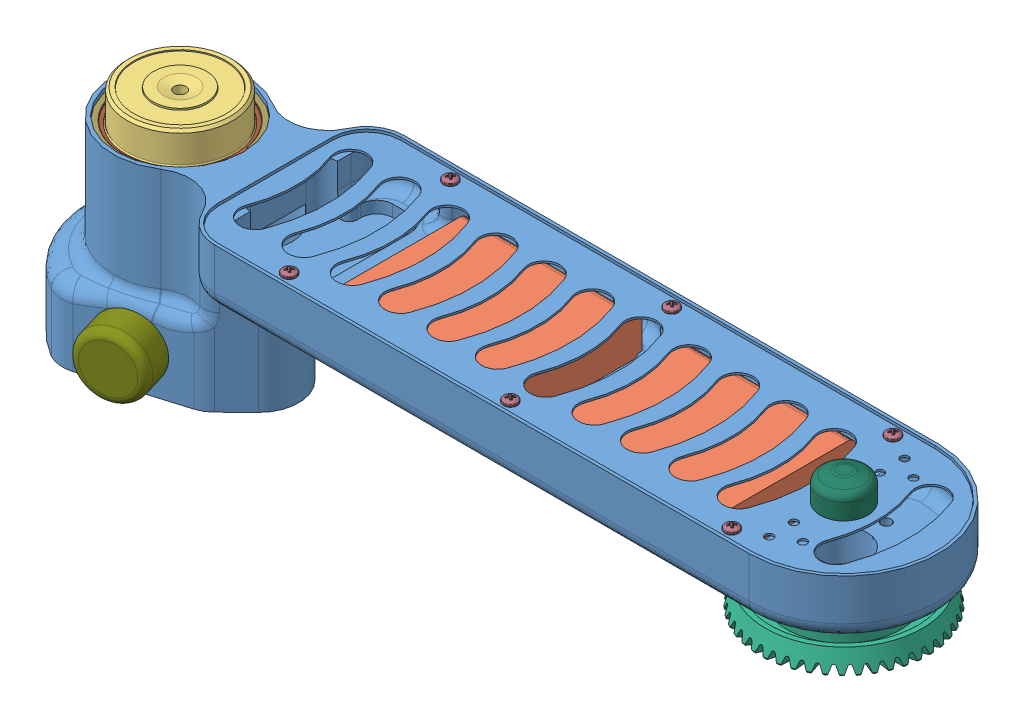
SolidWorks assembly 1001-2003 BATTERY LINK ASSY, configuration replacement encoder. Lengths in mm.
Overall size (351.62 112.52 93.62).
54 component instances, 21 part files, 75 mates.
Components (placement in the parent):
- 1001-3013,3014,3015 BATTERY LINK HOUSING & COVERS-1: 1001-3013,3014,3015 BATTERY LINK HOUSING & COVERS [Default] at origin size (342.9 76.2 76.2)
- 1001-3013,3014,3015 BATTERY LINK HOUSING & COVERS-3: 1001-3013,3014,3015 BATTERY LINK HOUSING & COVERS [palmar cover] at origin size (265.18 0.79 73.41)
- 1001-3013,3014,3015 BATTERY LINK HOUSING & COVERS-4: 1001-3013,3014,3015 BATTERY LINK HOUSING & COVERS [dorsal cover] at origin size (82.93 0.79 67.11)
- Battery 18650-1: Battery 18650 [Default] at (-92.71 10.3683 0) x (0 0 -1) z (1 0 0) size (55 18 70)
- Battery 18650-2: Battery 18650 [Default] at (-108.585 10.3683 0) x (0 0 1) z (-1 0 0) size (55 18 70)
- 1001-2001 ELECTROMAGNET ASSY-1: 1001-2001 ELECTROMAGNET ASSY [rev 03] at (-266.7 9.4082 0) x (-1 0 0) z (0 0 -1) size (50.7 33.97 50.7)
  - 1001-3001,3002,3003,3004,0002 ELECTROMAGNET PARENT-5: 1001-3001,3002,3003,3004,0002 ELECTROMAGNET PARENT [rev 03 core] at origin size (21.31 33.97 21.31)
  - 1001-3001,3002,3003,3004,0002 ELECTROMAGNET PARENT-7: 1001-3001,3002,3003,3004,0002 ELECTROMAGNET PARENT [rev 03] at origin size (50.7 33.01 50.7)
  - 1001-3001,3002,3003,3004,0002 ELECTROMAGNET PARENT-8: 1001-3001,3002,3003,3004,0002 ELECTROMAGNET PARENT [rev 03 spool] at origin size (36.73 28.47 36.73)
  - 1001-3001,3002,3003,3004,0002 ELECTROMAGNET PARENT-9: 1001-3001,3002,3003,3004,0002 ELECTROMAGNET PARENT [rev 02 coils] at origin size (36.73 26.95 36.73)
- Bearing - Delrin 6455K640-3: Bearing - Delrin 6455K640 [6455K64] at (-266.7 4.5974 0) x (0.689582 0 -0.724208) z (0 -1 0) size (28.57 28.57 6.35)
- Bearing - Delrin 6455K640-2: Bearing - Delrin 6455K640 [6455K64] at (-266.7 -12.8524 0) x (0.125826 0 -0.992052) z (0 -1 0) size (28.57 28.57 6.35)
- 1001-3001,3002,3003,3004,0002 ELECTROMAGNET PARENT-2: 1001-3001,3002,3003,3004,0002 ELECTROMAGNET PARENT [shaft] at (-266.7 9.4082 0) x (-0.98953 0 0.144326) z (-0.144326 0 -0.98953) size (12.78 36.2 12.78)
- Retaining Ring 99142A480-3: Retaining Ring 99142A480 [99142A480] at (-266.7 -8.4074 0) x (0.903607 0 0.428363) z (-0.428363 0 0.903607) size (31.72 1.27 34.32)
- Retaining Ring 99142A480-2: Retaining Ring 99142A480 [99142A480] at (-266.7 0.1524 0) x (0.943591 0 -0.331114) z (-0.331114 0 -0.943591) size (31.72 1.27 34.32)
- 1001-3011 MODIFIED DRIVEN GEAR-1: 1001-3011 MODIFIED DRIVEN GEAR [modified] at (0 -4.3198 0) x (-0.866025 0 -0.5) z (-0.5 0 0.866025) size (68.51 10.99 68.55)
- Canon TR-36-1: Canon TR-36 [Default] at (-239.7 -34.78 0) x (0 0 -1) z (0 1 0) size (40 47 17) (suppressed, hidden)
- 98381A438 (1)-1: 98381A438 (1) [98381A438] at (-283.21 4.0132 0) x (0 1 0) z (-0.942328 0 0.334692) size (12.7 2.38 2.38)
- User Library-5mm led w_bushing-1: User Library-5mm led w_bushing [Default] at (-266.7 -38.8049 0) x (1 0 0) z (0 -1 0) size (7.72 8.43 36.02)
- 98511A521-7: 98511A521 [98511A521] at (0 11.9568 17) x (0.27318 0 -0.961963) z (0 1 0) size (7.92 7.92 18.45)
- Oring -133 McMaster 5577K133-1: Oring -133 McMaster 5577K133 [Default] at (-266.7 26.67 0) x (0.946468 0 0.322797) z (0 1 0) size (50.93 50.93 2.62)
- 1001-3005 ELECTROMAGNET STATOR SHIM-1: 1001-3005 ELECTROMAGNET STATOR SHIM [Default] at (-266.7 28.8138 0) size (50.42 0.1 50.42)
- 1001-3005 ELECTROMAGNET STATOR SHIM-2: 1001-3005 ELECTROMAGNET STATOR SHIM [Default] at (-266.7 28.9154 0) size (50.42 0.1 50.42)
- 1001-3005 ELECTROMAGNET STATOR SHIM-3: 1001-3005 ELECTROMAGNET STATOR SHIM [Default] at (-266.7 29.017 0) size (50.42 0.1 50.42)
- 1001-3005 ELECTROMAGNET STATOR SHIM-4: 1001-3005 ELECTROMAGNET STATOR SHIM [Default] at (-266.7 29.1186 0) size (50.42 0.1 50.42)
- VH_200-1: VH_200 [Default] at (-266.7 29.7301 0) size (51.85 0.82 52.25)
- 98511A521-9: 98511A521 [98511A521] at (-14.7224 11.9568 8.5) x (0.969674 0 -0.244401) z (0 1 0) size (7.92 7.92 18.45)
- 98511A521-10: 98511A521 [98511A521] at (-14.7224 11.9568 -8.5) x (0.696494 0 0.717562) z (0 1 0) size (7.92 7.92 18.45)
- 98511A521-11: 98511A521 [98511A521] at (0 11.9568 -17) x (-0.27318 0 0.961963) z (0 1 0) size (7.92 7.92 18.45)
- 98511A521-12: 98511A521 [98511A521] at (14.7224 11.9568 -8.5) x (-0.969674 0 0.244401) z (0 1 0) size (7.92 7.92 18.45)
- 98511A521-13: 98511A521 [98511A521] at (14.7224 11.9568 8.5) x (-0.696494 0 -0.717562) z (0 1 0) size (7.92 7.92 18.45)
- 96562A106-1: 96562A106 [96562A106] at (-279.4 -37.3062 29.845) x (0.996675 0 -0.081481) z (0 -1 0) size (5.56 5.56 27.75)
- 96562A106-2: 96562A106 [96562A106] at (-279.4 -37.3062 -29.845) x (0.996675 0 -0.081481) z (0 -1 0) size (5.56 5.56 27.75)
- 96562A106-3: 96562A106 [96562A106] at (-190.5 24.4157 -32.385) x (-0.78982 0 -0.613339) z (0 1 0) size (5.56 5.56 27.75)
- 96562A106-4: 96562A106 [96562A106] at (-190.5 24.4157 32.385) x (-0.78982 0 -0.613339) z (0 1 0) size (5.56 5.56 27.75)
- 96562A106-5: 96562A106 [96562A106] at (-101.6 24.4157 32.385) x (-0.78982 0 -0.613339) z (0 1 0) size (5.56 5.56 27.75)
- 96562A106-6: 96562A106 [96562A106] at (-12.7 24.4157 32.385) x (-0.78982 0 -0.613339) z (0 1 0) size (5.56 5.56 27.75)
- 96562A106-7: 96562A106 [96562A106] at (-101.6 24.4157 -32.385) x (-0.78982 0 -0.613339) z (0 1 0) size (5.56 5.56 27.75)
- 96562A106-8: 96562A106 [96562A106] at (-12.7 24.4157 -32.385) x (-0.78982 0 -0.613339) z (0 1 0) size (5.56 5.56 27.75)
- 90272A091-1: 90272A091 [90272A091] at (-284.7 -14.0175 0) x (1 0 0) z (0 -1 0) size (4.9 4.9 6.71) (suppressed, hidden)
- 90272A091-2: 90272A091 [90272A091] at (-257.7 -14.0175 15.5885) x (-0.5 0 -0.866025) z (0 -1 0) size (4.9 4.9 6.71)
- 90272A091-3: 90272A091 [90272A091] at (-257.7 -14.0175 -15.5885) x (-0.5 0 0.866025) z (0 -1 0) size (4.9 4.9 6.71)
- 98381A438 (1)-3: 98381A438 (1) [98381A438] at (-270.5958 8.1382 0.5682) x (0 -1 0) z (-0.60583 0 -0.795594) size (12.7 2.38 2.38)
- 1001-3012 BALL GLIDER-1: 1001-3012 BALL GLIDER [Default] at (0 30.7658 0) x (0.866025 0 0.5) z (-0.5 0 0.866025) size (19.05 11.03 19.05)
- 96562A106-9: 96562A106 [96562A106] at (5.715 36.322 0) x (0.996675 0 -0.081481) z (0 -1 0) size (5.56 5.56 27.75)
- 96562A106-10: 96562A106 [96562A106] at (-2.8575 36.322 4.9493) x (-0.427773 0 0.903886) z (0 -1 0) size (5.56 5.56 27.75)
- 96562A106-11: 96562A106 [96562A106] at (-2.8575 36.322 -4.9493) x (-0.568902 0 -0.822405) z (0 -1 0) size (5.56 5.56 27.75)
- Bumper 9541K3-1: Bumper 9541K3 [Default] at (-257.9158 -29.5275 29.1868) x (0.916943 -0.288196 -0.275968) z (-0.275968 -0.957571 0.083057) size (25.4 22.23 25.4)
- Bumper 9541K3-2: Bumper 9541K3 [Default] at (-257.9158 -29.5275 -29.1868) x (-0.916943 -0.288196 -0.275968) z (0.275968 -0.957571 0.083057) size (25.4 22.23 25.4)
- Locknut 94820A225-1: Locknut 94820A225 [94820A225] at (-258.6478 -29.5275 26.7545) x (0.957571 0 -0.288196) z (0.288196 0 0.957571) size (9.53 11 6.84)
- Locknut 94820A225-2: Locknut 94820A225 [94820A225] at (-258.6478 -29.5275 -26.7545) x (-0.957571 0 -0.288196) z (0.288196 0 -0.957571) size (9.53 11 6.84)
- E7P-X-197-S-C-T-X-1: E7P-X-197-S-C-T-X [Default] at (-266.7 -17.907 0) x (-0.056079 0 0.998426) z (0.998426 0 0.056079)
- Retaining Ring 97633A200-1: Retaining Ring 97633A200 [97633A200] at (-266.7 -16.4719 0) x (0 1 0) z (0 0 1) size (0.89 19.18 19.18)
- 91251A113-1: 91251A113 [91251A113] at (-266.7 3.6932 0) x (0.186333 0 -0.982487) z (0 -1 0) size (4.65 4.65 22.59)
Mates (geometry in assembly coordinates):
- Coincident38: coincident anti-aligned: plane of 1001-3013,3014,3015 BATTERY LINK HOUSING & COVERS-1 through (0 0 0) normal (0 0 1); plane of Battery 18650-1 through (-92.71 10.3683 0) normal (0 0 -1)
- Coincident41: coincident aligned: plane of Battery 18650-1; plane of Battery 18650-2
- Coincident42: coincident anti-aligned: plane of Battery 18650-1 through (-92.71 10.3683 0) normal (0 0 -1); plane of Battery 18650-2 through (-108.585 10.3683 0) normal (0 0 1)
- Coincident43: coincident anti-aligned: line of 1001-3013,3014,3015 BATTERY LINK HOUSING & COVERS-1 through (-266.7 -48.26 0) axis (0 1 0); line of ? through (-266.7 43.4918 0) axis (0 -1 0)
- Coincident482: coincident anti-aligned: line of 1001-3013,3014,3015 BATTERY LINK HOUSING & COVERS-1 through (0 35.56 0) axis (0 -1 0); line of 1001-3011 MODIFIED DRIVEN GEAR-1 through (0 -9.7067 0) axis (0 1 0)
- Angle1: planar angle = 0.523599 rad aligned: plane of 1001-3011 MODIFIED DRIVEN GEAR-1 through (0 -4.3198 0) normal (-0.5 0 0.866025); plane of assembly through (0 0 0) normal (0 0 1)
- Coincident484: coincident anti-aligned: line of 1001-3013,3014,3015 BATTERY LINK HOUSING & COVERS-1 through (-266.7 -48.26 0) axis (0 1 0); line of 1001-3001,3002,3003,3004,0002 ELECTROMAGNET PARENT-2 through (-266.7 42.9768 0) axis (0 -1 0)
- Coincident485: coincident aligned: line of 1001-3013,3014,3015 BATTERY LINK HOUSING & COVERS-1 through (-266.7 -48.26 0) axis (0 1 0); line of Retaining Ring 99142A480-2 through (-266.7 0.0889 0) axis (0 1 0)
- Coincident486: coincident anti-aligned: line of 1001-3013,3014,3015 BATTERY LINK HOUSING & COVERS-1 through (-266.7 -48.26 0) axis (0 1 0); line of Retaining Ring 99142A480-3 through (-266.7 -8.3439 0) axis (0 -1 0)
- Coincident487: coincident aligned: line of 1001-3013,3014,3015 BATTERY LINK HOUSING & COVERS-1 through (-266.7 -48.26 0) axis (0 1 0); line of Bearing - Delrin 6455K640-2 through (-266.7 -9.6774 0) axis (0 1 0)
- Coincident488: coincident aligned: line of 1001-3013,3014,3015 BATTERY LINK HOUSING & COVERS-1 through (-266.7 -48.26 0) axis (0 1 0); line of Bearing - Delrin 6455K640-3 through (-266.7 7.7724 0) axis (0 1 0)
- Coincident489: coincident anti-aligned: plane of 1001-3013,3014,3015 BATTERY LINK HOUSING & COVERS-1 through (-280.8986 0.1524 0) normal (0 1 0); plane of Retaining Ring 99142A480-2 through (-263.1045 0.1524 -13.0915) normal (0 -1 0)
- Coincident490: coincident anti-aligned: plane of 1001-3013,3014,3015 BATTERY LINK HOUSING & COVERS-1 through (-281.9146 -8.4074 0) normal (0 -1 0); plane of Retaining Ring 99142A480-3 through (-264.499 -8.4074 13.3967) normal (0 1 0)
- Coincident491: coincident anti-aligned: plane of Bearing - Delrin 6455K640-2 through (-252.841 -9.6774 1.7578) normal (0 1 0); plane of Retaining Ring 99142A480-3 through (-264.499 -9.6774 13.3967) normal (0 -1 0)
- Coincident492: coincident anti-aligned: plane of Bearing - Delrin 6455K640-3 through (-256.5828 1.4224 9.6335) normal (0 -1 0); plane of Retaining Ring 99142A480-2 through (-263.1045 1.4224 -13.0915) normal (0 1 0)
- Distance13: distance = 0.7595 mm anti-aligned: plane of 1001-3013,3014,3015 BATTERY LINK HOUSING & COVERS-1 through (-280.8986 7.8232 0) normal (0 1 0); plane of 1001-2001 ELECTROMAGNET ASSY-1/1001-3001,3002,3003,3004,0002 ELECTROMAGNET PARENT-7 through (-248.412 8.5827 0) normal (0 -1 0)
- Coincident497: coincident anti-aligned: plane of ? through (-266.7 9.4082 0) normal (0 0 -1); plane of assembly through (0 0 0) normal (0 0 1)
- Concentric1: concentric aligned: cylinder of 1001-3013,3014,3015 BATTERY LINK HOUSING & COVERS-1 through (-283.21 7.8232 0) axis (0 1 0) radius 1.1906; cylinder of 98381A438 (1)-1 through (-283.21 -2.3368 0) axis (0 1 0) radius 1.1906
- Distance14: distance = 2.54 mm aligned: plane of 1001-3013,3014,3015 BATTERY LINK HOUSING & COVERS-1 through (-280.8986 7.8232 0) normal (0 1 0); plane of 98381A438 (1)-1 through (-283.21 10.3632 0) normal (0 1 0)
- Coincident5134: coincident anti-aligned: line of 1001-3013,3014,3015 BATTERY LINK HOUSING & COVERS-1 through (-266.7 -48.26 0) axis (0 1 0); line of Oring -133 McMaster 5577K133-1 through (-266.7 44.8023 0) axis (0 -1 0)
- Coincident5135: coincident anti-aligned: plane of 1001-2001 ELECTROMAGNET ASSY-1/1001-3001,3002,3003,3004,0002 ELECTROMAGNET PARENT-7 through (-244.6972 28.8138 0) normal (0 1 0); plane of 1001-3005 ELECTROMAGNET STATOR SHIM-1 through (-266.7 28.8138 0) normal (0 -1 0)
- Coincident5136: coincident aligned: line of 1001-3005 ELECTROMAGNET STATOR SHIM-1 through (-266.7 28.9204 0) axis (0 -1 0); line of ? through (-266.7 43.4918 0) axis (0 -1 0)
- Coincident5137: coincident anti-aligned: line of 1001-3005 ELECTROMAGNET STATOR SHIM-1 through (-266.7 28.9204 0) axis (0 -1 0); line of 1001-3013,3014,3015 BATTERY LINK HOUSING & COVERS-1 through (-266.7 -48.26 0) axis (0 1 0)
- Coincident5138: coincident anti-aligned: line of 1001-3013,3014,3015 BATTERY LINK HOUSING & COVERS-1 through (-266.7 -48.26 0) axis (0 1 0); line of VH_200-1 through (-266.7 30.1772 0) axis (0 -1 0)
- Coincident5139: coincident anti-aligned: plane of 1001-3013,3014,3015 BATTERY LINK HOUSING & COVERS-1 through (-292.825 30.1238 0) normal (0 -1 0); plane of VH_200-1 through (-240.773 30.1238 0) normal (0 1 0)
- Distance15: distance = 26.67 mm aligned: plane of Oring -133 McMaster 5577K133-1 through (-266.7 26.67 0) normal (0 1 0); plane of assembly through (0 0 0) normal (0 1 0)
- Concentric102: concentric anti-aligned: cylinder of 1001-3011 MODIFIED DRIVEN GEAR-1 through (0 -5.5692 17) axis (0 -1 0) radius 2.5527; cylinder of 98511A521-7 through (0 -5.5692 17) axis (0 1 0) radius 3.9624
- Coincident5140: coincident anti-aligned: plane of 1001-3011 MODIFIED DRIVEN GEAR-1 through (12.5117 -0.7432 7.2237) normal (0 -1 0); plane of 98511A521-7 through (0 -0.7432 17) normal (0 1 0)
- Coincident5141: coincident anti-aligned: plane of 1001-3013,3014,3015 BATTERY LINK HOUSING & COVERS-1 through (0 2.4308 0) normal (0 -1 0); plane of 1001-3011 MODIFIED DRIVEN GEAR-1 through (0 2.4308 0) normal (0 1 0)
- Coincident5142: coincident anti-aligned: plane of 1001-3013,3014,3015 BATTERY LINK HOUSING & COVERS-1 through (-234.95 10.3683 0) normal (0 1 0); plane of Battery 18650-1 through (-22.71 10.3683 24.325) normal (0 -1 0)
- Coincident5143: coincident anti-aligned: plane of 1001-3013,3014,3015 BATTERY LINK HOUSING & COVERS-1 through (-298.45 -17.78 0) normal (0 -1 0); plane of Canon TR-36-1 through (-266.7 -17.78 0) normal (0 1 0)
- Coincident5144: coincident anti-aligned: line of 1001-3013,3014,3015 BATTERY LINK HOUSING & COVERS-1 through (-266.7 -48.26 0) axis (0 1 0); line of Canon TR-36-1 through (-266.7 -18.78 0) axis (0 -1 0)
- Coincident5145: coincident anti-aligned: plane of Canon TR-36-1; plane of assembly through (0 0 0) normal (0 0 1)
- Coincident5146: coincident aligned: plane of 1001-3013,3014,3015 BATTERY LINK HOUSING & COVERS-3 through (0 0 0) normal (0 0 1); plane of assembly through (0 0 0) normal (0 0 1)
- Coincident5147: coincident aligned: plane of 1001-3013,3014,3015 BATTERY LINK HOUSING & COVERS-3 through (0 0 0) normal (0 1 0); plane of assembly through (0 0 0) normal (0 1 0)
- Coincident5148: coincident aligned: plane of 1001-3013,3014,3015 BATTERY LINK HOUSING & COVERS-3 through (0 0 0) normal (1 0 0); plane of assembly through (0 0 0) normal (1 0 0)
- Coincident5149: coincident aligned: plane of 1001-3013,3014,3015 BATTERY LINK HOUSING & COVERS-4 through (0 0 0) normal (0 0 1); plane of assembly through (0 0 0) normal (0 0 1)
- Coincident5150: coincident aligned: plane of 1001-3013,3014,3015 BATTERY LINK HOUSING & COVERS-4 through (0 0 0) normal (0 1 0); plane of assembly through (0 0 0) normal (0 1 0)
- Coincident5151: coincident aligned: plane of 1001-3013,3014,3015 BATTERY LINK HOUSING & COVERS-4 through (0 0 0) normal (1 0 0); plane of assembly through (0 0 0) normal (1 0 0)
- Concentric103: concentric aligned: cylinder of 1001-3013,3014,3015 BATTERY LINK HOUSING & COVERS-4 through (-266.7 -43.6562 0) axis (0 -1 0) radius 3.175; cylinder of User Library-5mm led w_bushing-1 through (-266.7 -49.028 0) axis (0 -1 0) radius 2.9972
- Coincident5152: coincident aligned: plane of 1001-3013,3014,3015 BATTERY LINK HOUSING & COVERS-4 through (-278.9455 -43.6562 -22.2533) normal (0 -1 0); circle of User Library-5mm led w_bushing-1
- Concentric104: concentric anti-aligned: cylinder of 1001-3013,3014,3015 BATTERY LINK HOUSING & COVERS-1 through (-279.4 -42.8625 29.845) axis (0 -1 0) radius 1.1303; cylinder of 96562A106-1 through (-279.4 -37.3062 29.845) axis (0 1 0) radius 2.7813
- Coincident5153: coincident anti-aligned: plane of 1001-3013,3014,3015 BATTERY LINK HOUSING & COVERS-4 through (-278.9455 -43.6562 -22.2533) normal (0 -1 0); plane of 96562A106-1 through (-279.4 -43.6562 29.845) normal (0 1 0)
- Coincident5154: coincident anti-aligned: plane of 1001-3013,3014,3015 BATTERY LINK HOUSING & COVERS-4 through (-278.9455 -43.6562 -22.2533) normal (0 -1 0); plane of 96562A106-2 through (-279.4 -43.6562 -29.845) normal (0 1 0)
- Concentric105: concentric anti-aligned: cylinder of 1001-3013,3014,3015 BATTERY LINK HOUSING & COVERS-4 through (-279.4 -43.6562 -29.845) axis (0 -1 0) radius 1.632; cylinder of 96562A106-2 through (-279.4 -37.3062 -29.845) axis (0 1 0) radius 2.7813
- Concentric106: concentric anti-aligned: cylinder of 96562A106-3 through (-190.5 24.4157 -32.385) axis (0 -1 0) radius 2.7813; cylinder of 1001-3013,3014,3015 BATTERY LINK HOUSING & COVERS-1 through (-190.5 29.972 -32.385) axis (0 1 0) radius 1.1303
- Coincident5155: coincident anti-aligned: plane of 1001-3013,3014,3015 BATTERY LINK HOUSING & COVERS-3 through (-214.757 30.7658 -22.987) normal (0 1 0); plane of 96562A106-3 through (-190.5 30.7658 -32.385) normal (0 -1 0)
- Coincident5156: coincident anti-aligned: plane of 1001-3013,3014,3015 BATTERY LINK HOUSING & COVERS-3 through (-214.757 30.7658 -22.987) normal (0 1 0); plane of 96562A106-4 through (-190.5 30.7658 32.385) normal (0 -1 0)
- Concentric107: concentric anti-aligned: cylinder of 1001-3013,3014,3015 BATTERY LINK HOUSING & COVERS-1 through (-190.5 29.972 32.385) axis (0 1 0) radius 1.1303; cylinder of 96562A106-4 through (-190.5 24.4157 32.385) axis (0 -1 0) radius 2.7813
- Coincident5158: coincident anti-aligned: plane of Canon TR-36-1 through (-266.7 -18.78 0) normal (0 -1 0); plane of 90272A091-1 through (-284.7 -18.78 0) normal (0 1 0)
- Concentric109: concentric anti-aligned: cylinder of 1001-3013,3014,3015 BATTERY LINK HOUSING & COVERS-1 through (-284.7 -17.78 0) axis (0 -1 0) radius 0.9969; cylinder of 90272A091-1 through (-284.7 -14.0175 0) axis (0 1 0) radius 2.4511
- Concentric1101: concentric anti-aligned: cylinder of 1001-3001,3002,3003,3004,0002 ELECTROMAGNET PARENT-2 through (-270.5958 9.4082 0.5682) axis (0 1 0) radius 1.1906; cylinder of 98381A438 (1)-3 through (-270.5958 14.4882 0.5682) axis (0 -1 0) radius 1.1906
- Coincident51591: coincident anti-aligned: circle of 1001-3001,3002,3003,3004,0002 ELECTROMAGNET PARENT-2; plane of 98381A438 (1)-3 through (-270.5958 1.7882 0.5682) normal (0 -1 0)
- Concentric1111: concentric anti-aligned: cylinder of 1001-3013,3014,3015 BATTERY LINK HOUSING & COVERS-3 through (5.715 30.7658 0) axis (0 1 0) radius 1.632; cylinder of 1001-3012 BALL GLIDER-1 through (5.715 30.7658 0) axis (0 -1 0) radius 1.1303
- Concentric1121: concentric anti-aligned: cylinder of 1001-3013,3014,3015 BATTERY LINK HOUSING & COVERS-3 through (-2.8575 30.7658 4.9493) axis (0 1 0) radius 1.632; cylinder of 1001-3012 BALL GLIDER-1 through (-2.8575 30.7658 4.9493) axis (0 -1 0) radius 1.1303
- Coincident51601: coincident anti-aligned: plane of 1001-3013,3014,3015 BATTERY LINK HOUSING & COVERS-3 through (-214.757 30.7658 -22.987) normal (0 1 0); plane of 1001-3012 BALL GLIDER-1 through (-8.2489 30.7658 -4.7625) normal (0 -1 0)
- Concentric113: concentric aligned: cylinder of 1001-3013,3014,3015 BATTERY LINK HOUSING & COVERS-3 through (5.715 30.7658 0) axis (0 1 0) radius 1.632; cylinder of 96562A106-9 through (5.715 36.322 0) axis (0 1 0) radius 2.7813
- Coincident5161: coincident anti-aligned: plane of 1001-3013,3014,3015 BATTERY LINK HOUSING & COVERS-3 through (-214.757 29.972 -22.987) normal (0 -1 0); plane of 96562A106-9 through (5.715 29.972 0) normal (0 1 0)
- Concentric1122: concentric aligned: cylinder of 1001-3013,3014,3015 BATTERY LINK HOUSING & COVERS-1 through (-257.9158 -29.5275 29.1868) axis (0.288196 0 0.957571) radius 2.5527; cylinder of Bumper 9541K3-1 through (-242.7855 -29.5275 79.4593) axis (0.288196 0 0.957571) radius 2.413
- Coincident51608: coincident anti-aligned: plane of 1001-3013,3014,3015 BATTERY LINK HOUSING & COVERS-1 through (-279.8059 31.75 35.7749) normal (0.288196 0 0.957571); plane of Bumper 9541K3-1 through (-260.1284 -28.8321 29.8527) normal (-0.288196 0 -0.957571)
- Concentric1123: concentric aligned: cylinder of 1001-3013,3014,3015 BATTERY LINK HOUSING & COVERS-1 through (-257.9158 -29.5275 -29.1868) axis (0.288196 0 -0.957571) radius 2.5527; cylinder of Bumper 9541K3-2 through (-242.7855 -29.5275 -79.4593) axis (0.288196 0 -0.957571) radius 2.413
- Coincident51609: coincident anti-aligned: plane of 1001-3013,3014,3015 BATTERY LINK HOUSING & COVERS-1 through (-279.8059 31.75 -35.7749) normal (0.288196 0 -0.957571); plane of Bumper 9541K3-2 through (-255.7032 -28.8321 -28.5209) normal (-0.288196 0 0.957571)
- Concentric1124: concentric anti-aligned: cylinder of Bumper 9541K3-1 through (-242.7855 -29.5275 79.4593) axis (0.288196 0 0.957571) radius 2.413; cylinder of Locknut 94820A225-1 through (-260.0661 -29.5275 22.0421) axis (-0.288196 0 -0.957571) radius 2.8956
- Coincident51610: coincident anti-aligned: plane of 1001-3013,3014,3015 BATTERY LINK HOUSING & COVERS-1 through (-238.7446 85.6903 20.7644) normal (-0.288196 0 -0.957571); plane of Locknut 94820A225-1 through (-263.2082 -21.2786 28.1271) normal (0.288196 0 0.957571)
- Concentric1125: concentric anti-aligned: cylinder of Bumper 9541K3-2 through (-242.7855 -29.5275 -79.4593) axis (0.288196 0 -0.957571) radius 2.413; cylinder of Locknut 94820A225-2 through (-260.0661 -29.5275 -22.0421) axis (-0.288196 0 0.957571) radius 2.8956
- Coincident51611: coincident anti-aligned: plane of 1001-3013,3014,3015 BATTERY LINK HOUSING & COVERS-1 through (-276.0174 85.6903 -31.9822) normal (-0.288196 0 0.957571); plane of Locknut 94820A225-2 through (-254.0874 -21.2786 -25.382) normal (0.288196 0 -0.957571)
- Concentric1126: concentric anti-aligned: line of 1001-3013,3014,3015 BATTERY LINK HOUSING & COVERS-1 through (-266.7 -48.26 0) axis (0 1 0); cone of E7P-X-197-S-C-T-X-1 through (-266.7 -19.177 0) axis (0 -1 0)
- Coincident51612: coincident anti-aligned: plane of 1001-3013,3014,3015 BATTERY LINK HOUSING & COVERS-1 through (-298.45 -17.78 0) normal (0 -1 0); plane of E7P-X-197-S-C-T-X-1 through (-266.7 -17.78 0) normal (0 1 0)
- Coincident51613: coincident anti-aligned: plane of 1001-2001 ELECTROMAGNET ASSY-1/1001-3001,3002,3003,3004,0002 ELECTROMAGNET PARENT-5 through (-260.3119 9.4082 0) normal (0 -1 0); plane of 1001-3001,3002,3003,3004,0002 ELECTROMAGNET PARENT-2 through (-266.7 9.4082 0) normal (0 1 0)
- Concentric1127: concentric anti-aligned: line of 1001-3013,3014,3015 BATTERY LINK HOUSING & COVERS-1 through (-266.7 -48.26 0) axis (0 1 0); cylinder of Retaining Ring 97633A200-1 through (-266.7 -16.0274 0) axis (0 -1 0) radius 5.8547
- Coincident51615: coincident anti-aligned: plane of Bearing - Delrin 6455K640-2 through (-257.4324 -16.0274 1.1754) normal (0 -1 0); plane of Retaining Ring 97633A200-1 through (-266.7 -16.0274 0) normal (0 1 0)
- Concentric1128: concentric anti-aligned: line of 1001-3013,3014,3015 BATTERY LINK HOUSING & COVERS-1 through (-266.7 -48.26 0) axis (0 1 0); cylinder of 91251A113-1 through (-266.7 25.588 0) axis (0 -1 0) radius 2.3241
- Coincident51617: coincident anti-aligned: plane of 1001-2001 ELECTROMAGNET ASSY-1/1001-3001,3002,3003,3004,0002 ELECTROMAGNET PARENT-5 through (-268.224 22.7432 0) normal (0 1 0); plane of 91251A113-1 through (-266.7 22.7432 0) normal (0 -1 0)
- Distance16: distance = 15.875 mm anti-aligned: plane of Battery 18650-2 through (-108.585 10.3683 0) normal (-1 0 0); plane of Battery 18650-1 through (-92.71 10.3683 0) normal (1 0 0)
- Distance17: distance = 3.175 mm aligned: plane of 1001-3013,3014,3015 BATTERY LINK HOUSING & COVERS-1 through (-95.885 -87.4882 -22.225) normal (1 0 0); plane of Battery 18650-1 through (-92.71 10.3683 0) normal (1 0 0)
